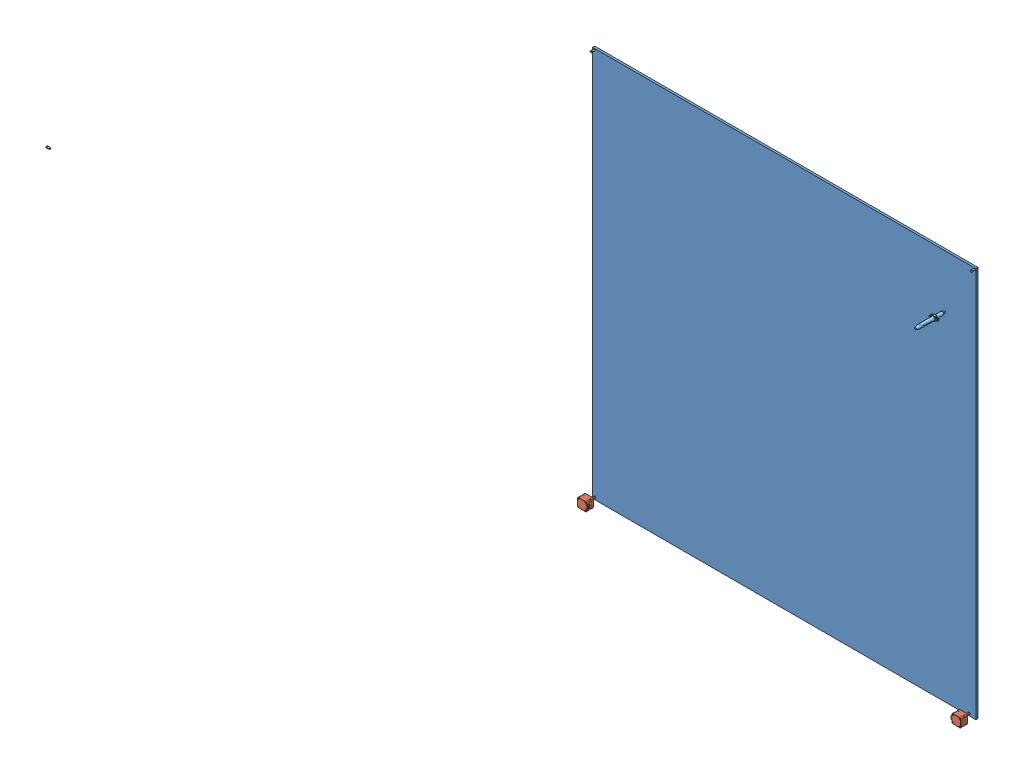
SolidWorks assembly Ensamble, configuration Default. Lengths in mm.
Overall size (2542.65 5240.27 5101.41).
11 component instances, 6 part files, 21 mates.
Components (placement in the parent):
- soporte-1: soporte [Default] at (50.166 1554.9429 3620.4032) size (1797.77 1832.77 20)
- StepperMotor-1: StepperMotor [Default] at (56.166 1525.9429 3667.9032) x (0 0 1) z (0 -1 0) size (56 48 42)
- StepperMotor-2: StepperMotor [Default] at (1811.933 1525.9429 3667.9032) x (0 0 1) z (0 1 0) size (56 48 42)
- Polea-1: Polea [Default] at (56.166 1525.9429 3645.4032) x (0 0 1) z (-1 0 0) size (15 8 8)
- Polea-2: Polea [Default] at (2567.819 6741.2097 8717.8157) size (15 8 8)
- Polea-3: Polea [Default] at (1825.433 3330.2098 3640.4032) x (0 0 -1) z (1 0 0) size (15 8 8)
- Polea-4: Polea [Default] at (1811.933 1525.9429 3645.4032) x (0 0 1) z (-0.77933 0.626614 0) size (15 8 8)
- MordazaInferior-1: MordazaInferior [Default] at (1691.421 3093.9382 3679.1712) x (-1 0 0) z (0 0 1) size (37 11.01 10)
- marcador-1: marcador [Default] at (1691.421 3093.9382 3679.1712) x (-0.050675 0.998715 0) z (0.998715 0.050675 0) size (17.02 141.48 17.15)
- MordazaSuperior-1: MordazaSuperior [Default] at (1691.421 3093.9382 3679.1712) size (37 11.16 10)
- Polea-5: Polea [Default] at (42.666 3330.2098 3640.4032) x (0 0 -1) z (1 0 0) size (15 8 8)
Mates (geometry in assembly coordinates):
- Concentric1: concentric aligned: circle of marcador-1; circle of MordazaSuperior-1
- Coincident1: coincident aligned: plane of marcador-1 through (1690.9898 3102.4362 3679.1712) normal (0 0 -1); plane of MordazaSuperior-1 through (1691.421 3093.9382 3679.1712) normal (0 0 -1)
- Coincident2: coincident aligned: plane of MordazaInferior-1 through (1691.421 3093.9382 3679.1712) normal (0 0 -1); plane of marcador-1 through (1690.9898 3102.4362 3679.1712) normal (0 0 -1)
- Parallel1: parallel anti-aligned: plane of MordazaInferior-1 through (1699.9163 3093.4382 3689.1712) normal (0 1 0); plane of MordazaSuperior-1 through (1682.9257 3094.4382 3689.1712) normal (0 -1 0)
- Concentric2: concentric aligned: cylinder of MordazaInferior-1 through (1691.421 3093.9382 3689.1712) axis (0 0 -1) radius 8.51; cylinder of marcador-1 through (1691.421 3093.9382 3679.1712) axis (0 0 -1) radius 8.509
- Coincident4: coincident: plane of soporte-1 through (50.166 1554.9429 3630.4032) normal (0 0 1); point of marcador-1
- Parallel2: parallel aligned: plane of soporte-1 through (50.166 1554.9429 3630.4032) normal (0 0 1); plane of marcador-1 through (1691.421 3093.9382 3771.8812) normal (0 0 1)
- Concentric3: concentric aligned: cylinder of soporte-1 through (1825.433 3330.2098 3640.4032) axis (0 0 -1) radius 2.5; cylinder of Polea-3 through (1825.433 3330.2098 3640.4032) axis (0 0 -1) radius 2.5
- Coincident6: coincident anti-aligned: plane of soporte-1 through (1825.433 3330.2098 3640.4032) normal (0 0 1); plane of Polea-3 through (1825.433 3330.2098 3640.4032) normal (0 0 -1)
- Concentric4: concentric aligned: cylinder of soporte-1 through (42.666 3330.2098 3640.4032) axis (0 0 -1) radius 2.5; cylinder of Polea-5 through (42.666 3330.2098 3640.4032) axis (0 0 -1) radius 2.5
- Coincident7: coincident anti-aligned: plane of soporte-1 through (42.666 3330.2098 3640.4032) normal (0 0 1); plane of Polea-5 through (42.666 3330.2098 3640.4032) normal (0 0 -1)
- Coincident8: coincident anti-aligned: plane of StepperMotor-1 through (56.166 1525.9429 3645.4032) normal (0 0 -1); plane of Polea-1 through (56.166 1525.9429 3645.4032) normal (0 0 1)
- Concentric5: concentric aligned: cylinder of StepperMotor-1 through (56.166 1525.9429 3645.4032) axis (0 0 1) radius 2.5; cylinder of Polea-1 through (56.166 1525.9429 3645.4032) axis (0 0 1) radius 2.5
- Coincident9: coincident aligned: plane of Polea-1 through (56.166 1529.9429 3644.9032) normal (0 0 -1); plane of Polea-5 through (42.666 3333.7098 3644.9032) normal (0 0 -1)
- Coincident10: coincident aligned: plane of soporte-1 through (35.166 1504.9429 3630.4032) normal (0 -1 0); plane of StepperMotor-1 through (77.166 1504.9429 3701.4032) normal (0 -1 0)
- Coincident11: coincident aligned: plane of soporte-1 through (35.166 3337.7098 3630.4032) normal (-1 0 0); plane of StepperMotor-1 through (35.166 1504.9429 3701.4032) normal (-1 0 0)
- Coincident12: coincident anti-aligned: plane of StepperMotor-2 through (1811.933 1525.9429 3645.4032) normal (0 0 -1); plane of Polea-4 through (1811.933 1525.9429 3645.4032) normal (0 0 1)
- Concentric6: concentric aligned: cylinder of StepperMotor-2 through (1811.933 1525.9429 3645.4032) axis (0 0 1) radius 2.5; cylinder of Polea-4 through (1811.933 1525.9429 3645.4032) axis (0 0 1) radius 2.5
- Coincident13: coincident aligned: plane of soporte-1 through (35.166 1504.9429 3630.4032) normal (0 -1 0); plane of StepperMotor-2 through (1832.933 1504.9429 3701.4032) normal (0 -1 0)
- Coincident14: coincident aligned: plane of soporte-1 through (1832.933 3337.7098 3630.4032) normal (1 0 0); plane of StepperMotor-2 through (1832.933 1546.9429 3701.4032) normal (1 0 0)
- Coincident15: coincident aligned: plane of Polea-3 through (1825.433 3333.7098 3644.9032) normal (0 0 -1); plane of Polea-4 through (1814.4394 1529.0602 3644.9032) normal (0 0 -1)
